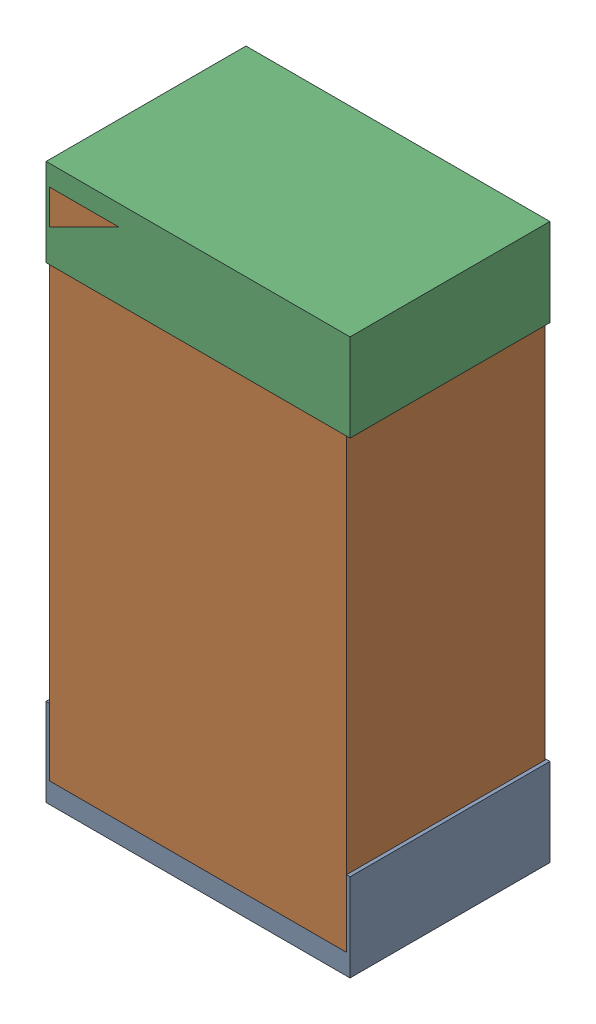
SolidWorks assembly R57Kanaloa_v2.0.0_Motor, configuration Default. Lengths in mm.
Overall size (1.3 2.38 0.85).
6 component instances, 2 part files, 0 mates.
Components (placement in the parent):
- 330415056-1: 330415056 [Default] at (138.684 153.686 -1.9574) size (1.3 0.38 0.85)
  - Extruded_2-1: Extruded_2 [Default] at origin size (1.3 0.38 0.85)
- 334787376-1: 334787376 [Default] at (138.684 154.686 -1.9524) size (1.27 2.2 0.85)
  - Extruded_16-1: Extruded_16 [Default] at origin size (1.27 2.2 0.85)
- 330415056-2: 330415056 [Default] at (138.684 155.686 -1.9574) size (1.3 0.38 0.85)
  - Extruded_2-1: Extruded_2 [Default] at origin size (1.3 0.38 0.85)
